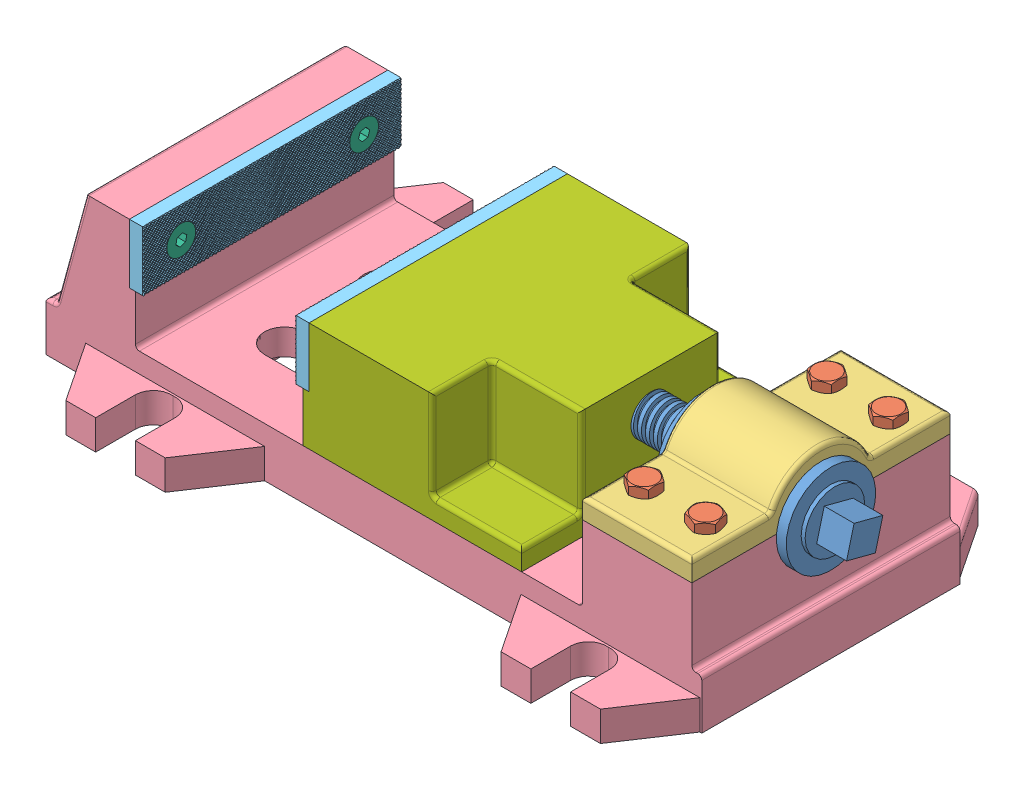
SolidWorks assembly Тиски - ЧМВ2.00.00, configuration По умолчанию. Lengths in mm.
Overall size (376.4 90 317.87).
20 component instances, 9 part files, 5 mates.
Components (placement in the parent):
- Основание - ЧМВ2.01.00-2: Основание - ЧМВ2.01.00 [По умолчанию] at origin size (376.4 90 317.87)
  - Вал - ЧМВ2.01.01-1: Вал - ЧМВ2.01.01 [По умолчанию] at (139.4504 77.8357 344.737) x (1 0 0) z (0 -0.252267 -0.967658) size (200 45 45)
  - Болт М20 - ЧМВ2.01.03-1: Болт М20 - ЧМВ2.01.03 [По умолчанию] at (174.4504 95.1357 390.737) x (-0.837169 0 -0.546944) z (-0.546944 0 0.837169) size (15.01 28.64 13)
  - Болт М20 - ЧМВ2.01.03-2: Болт М20 - ЧМВ2.01.03 [По умолчанию] at (205.4504 95.1357 390.737) x (-0.954672 0 -0.29766) z (-0.29766 0 0.954672) size (15.01 28.64 13)
  - Болт М20 - ЧМВ2.01.03-3: Болт М20 - ЧМВ2.01.03 [По умолчанию] at (205.4504 95.1357 298.737) x (-0.837169 0 -0.546944) z (-0.546944 0 0.837169) size (15.01 28.64 13)
  - Болт М20 - ЧМВ2.01.03-4: Болт М20 - ЧМВ2.01.03 [По умолчанию] at (174.4504 95.1357 298.737) x (-0.837169 0 -0.546944) z (-0.546944 0 0.837169) size (15.01 28.64 13)
  - Крышка - ЧМВ2.01.02-1: Крышка - ЧМВ2.01.02 [По умолчанию] at (217.4504 79.8357 344.737) x (0 0 1) z (-1 0 0) size (130 27 55)
  - Основа тисков - ЧМВ2.01.01-1: Основа тисков - ЧМВ2.01.01 [По умолчанию] at (32.9367 66.0161 279.737) size (376.4 80 317.87)
  - Губки для тисков - ЧМВ2.03.01-3: Губки для тисков - ЧМВ2.03.01 [По умолчанию] at (-65.5496 81.8357 344.737) x (0 0 -1) z (1 0 0) size (130 30 7.06)
  - Винт М8 - ЧМВ2.03.02-3: Винт М8 - ЧМВ2.03.02 [По умолчанию] at (-58.4596 81.8357 390.737) x (0 0.782667 0.622441) z (1 0 0) size (14.5 14.5 20)
  - Винт М8 - ЧМВ2.03.02-4: Винт М8 - ЧМВ2.03.02 [По умолчанию] at (-58.4596 81.8357 298.737) x (0 -0.851898 -0.523708) z (1 0 0) size (14.5 14.5 20)
- Подвижная часть - ЧМВ2.02.00-2: Подвижная часть - ЧМВ2.02.00 [По умолчанию] at (55.3614 0 0) size (116.09 79.5 130)
  - Подвижная часть ред. - ЧМВ2.02.01-1: Подвижная часть ред. - ЧМВ2.02.01 [По умолчанию] at (21.4678 41.8357 344.737) size (112 68 130)
  - Шайба - ЧМВ2.02.03-1: Шайба - ЧМВ2.02.03 [По умолчанию] at (21.4678 26.8357 369.737) x (0.999511 0 -0.031261) z (0.031261 0 0.999511) size (35 2 35)
  - Шайба - ЧМВ2.02.03-2: Шайба - ЧМВ2.02.03 [По умолчанию] at (21.4678 26.8357 319.737) x (0.013506 0 -0.999909) z (0.999909 0 0.013506) size (35 2 35)
  - Болт М8 - ЧМВ2.02.02-1: Болт М8 - ЧМВ2.02.02 [По умолчанию] at (21.4678 17.3357 369.737) x (0.22437 0 0.974504) z (-0.974504 0 0.22437) size (30 58.5 25.98)
  - Болт М8 - ЧМВ2.02.02-2: Болт М8 - ЧМВ2.02.02 [По умолчанию] at (21.4678 17.3357 319.737) x (0.783213 0 -0.621753) z (0.621753 0 0.783213) size (30 58.5 25.98)
  - Винт М8 - ЧМВ2.03.02-3: Винт М8 - ЧМВ2.03.02 [По умолчанию] at (-37.6222 81.8357 298.737) x (0 0.266843 0.96374) z (-1 0 0) size (14.5 14.5 20)
  - Винт М8 - ЧМВ2.03.02-4: Винт М8 - ЧМВ2.03.02 [По умолчанию] at (-37.6222 81.8357 390.737) x (0 0.506287 0.862365) z (-1 0 0) size (14.5 14.5 20)
  - Губки для тисков - ЧМВ2.03.01-2: Губки для тисков - ЧМВ2.03.01 [По умолчанию] at (-30.5322 81.8357 344.737) x (0 0 1) z (-1 0 0) size (130 30 7.06)
Mates (geometry in assembly coordinates):
- Совпадение73: coincident anti-aligned: plane of Основание - ЧМВ2.01.00-2/Основа тисков - ЧМВ2.01.01-1 through (162.4504 41.8357 409.737) normal (0 1 0); plane of Подвижная часть - ЧМВ2.02.00-2/Подвижная часть ред. - ЧМВ2.02.01-1 through (76.8293 41.8357 344.737) normal (0 -1 0)
- Совпадение74: coincident anti-aligned: plane of Основание - ЧМВ2.01.00-2/Основа тисков - ЧМВ2.01.01-1 through (-27.5496 16.8357 309.737) normal (0 0 1); plane of Подвижная часть - ЧМВ2.02.00-2/Подвижная часть ред. - ЧМВ2.02.01-1 through (121.8293 28.8357 309.737) normal (0 0 -1)
- Совпадение76: coincident anti-aligned: plane of Основание - ЧМВ2.01.00-2/Основа тисков - ЧМВ2.01.01-1 through (32.9367 28.8357 279.737) normal (0 -1 0); plane of Подвижная часть - ЧМВ2.02.00-2/Шайба - ЧМВ2.02.03-2 through (76.8293 28.8357 319.737) normal (0 1 0)
- Граничное расстояние2: limit distance = 25.6212 mm anti-aligned: plane of Подвижная часть - ЧМВ2.02.00-2/Подвижная часть ред. - ЧМВ2.02.01-1 through (131.8293 96.8357 409.737) normal (1 0 0); plane of Основание - ЧМВ2.01.00-2/Вал - ЧМВ2.01.01-1 through (157.4504 68.1591 347.2597) normal (-1 0 0)
- Совпадение77: coordinate: point of Основание - ЧМВ2.01.00-2
